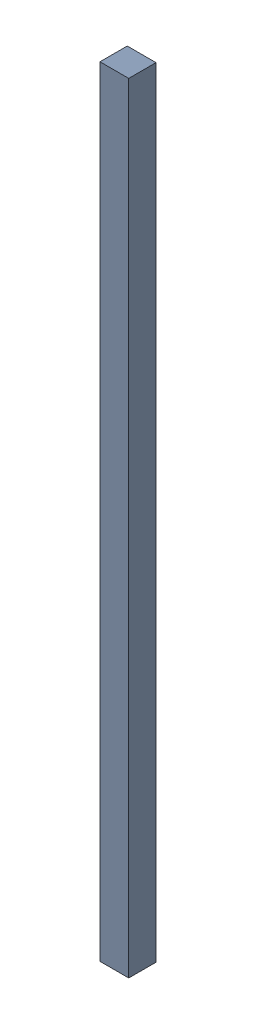
SolidWorks assembly Free-Models-2.step, configuration Default. Lengths in mm.
Overall size (0.47 12.7 0.45).
2 component instances, 1 part files, 0 mates.
Components (placement in the parent):
- 790454240.step-1: 790454240.step [Default] at (0 -6.35 -0.35) size (0.47 12.7 0.45)
  - Extruded-45.step-1: Extruded-45.step [Default] at origin size (0.47 12.7 0.45)
